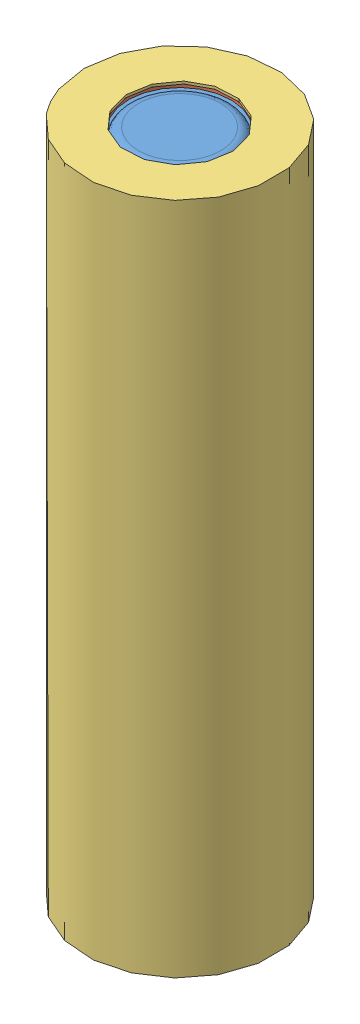
SolidWorks assembly 18650_wrapped, configuration Default. Lengths in mm.
Overall size (25.12 65.6 25.12).
3 component instances, 3 part files, 4 mates.
Components (placement in the parent):
- 18650-1: 18650 [Default] at origin size (18 65 18)
- Insulator_donut-1: Insulator_donut [Default] at (0 64.8 0) x (0.970599 0 -0.240704) z (0.240704 0 0.970599) size (18 0.3 18)
- 18650_Shrinkwarp-1: 18650_Shrinkwarp [Default] x (0.480873 0 0.87679) z (-0.87679 0 0.480873) size (18.5 65.6 18.5)
Mates (geometry in assembly coordinates):
- Coincident1: coincident: circle of assembly; plane of assembly; circle of 18650-1; plane of Insulator_donut-1 through (0 64.8 0) normal (0 -1 0)
- Concentric1: concentric: cylinder of assembly; cylinder of assembly; cylinder of 18650-1 through (0 65 0) axis (0 -1 0) radius 9; cylinder of Insulator_donut-1 through (0 65.1 0) axis (0 -1 0) radius 9
- Concentric2: concentric: cylinder of assembly; cylinder of assembly; cylinder of 18650-1 through (0 65 0) axis (0 -1 0) radius 9; cylinder of 18650_Shrinkwarp-1 through (0 65.1 0) axis (0 -1 0) radius 9
- Coincident2: coincident: plane of assembly; plane of assembly; plane of Insulator_donut-1 through (0 65.1 0) normal (0 1 0); plane of 18650_Shrinkwarp-1 through (0 65.1 0) normal (0 -1 0)
